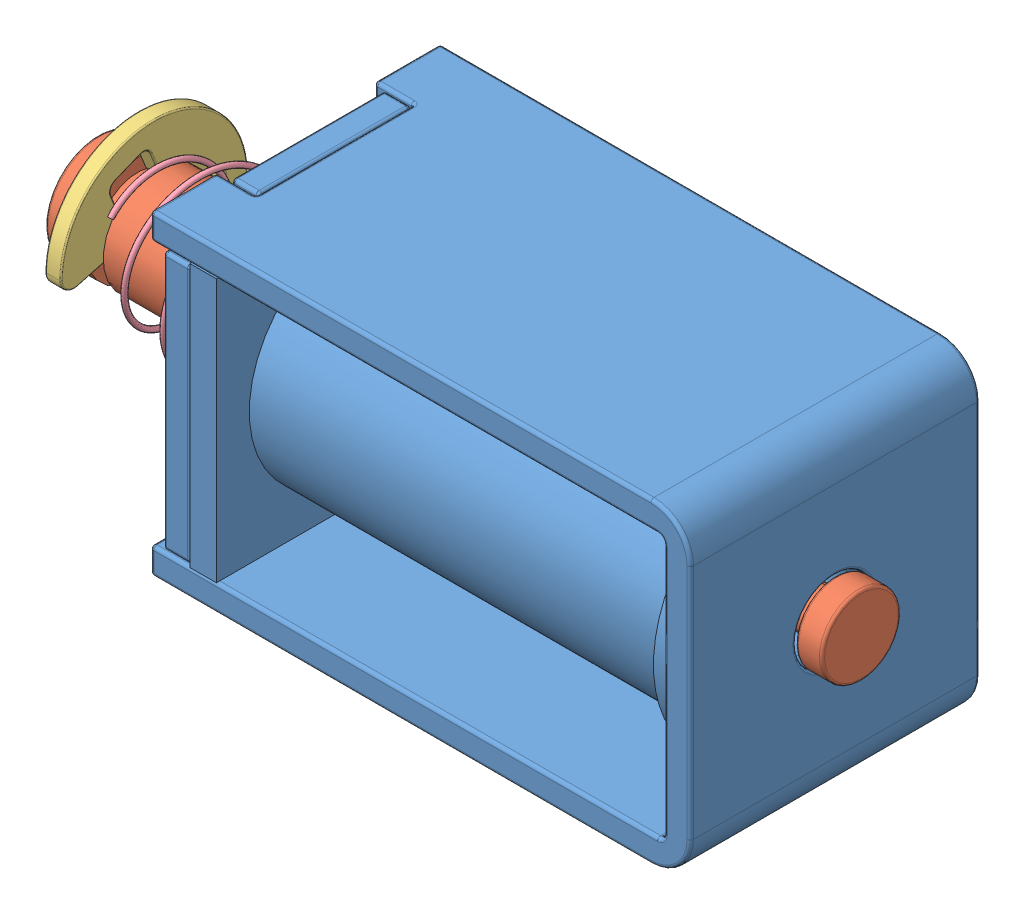
SolidWorks assembly Solenoid, configuration Default. Lengths in mm.
Overall size (29 12 11).
5 component instances, 4 part files, 3 mates.
Components (placement in the parent):
- Shell-1: Shell [Default] at origin size (20.5 12 11)
- Shaft Assem-1: Shaft Assem [Default] at (2.5 -6 5.5) x (0 0.575247 0.81798) z (1 0 0) size (7.1 6.76 29)
  - Shaft-1: Shaft [Default] at origin size (4 4 29)
  - Circlip-1: Circlip [Default] at (0 0 -8.45) size (7.1 5.79 0.6)
  - Spring-1: Spring [Default] at (0 0 -2.3) x (-1 0 0) z (0 0 -1) size (6.3 6.5 5.85)
Mates (geometry in assembly coordinates):
- Coincident1: coordinate: point of Shell-1; point of assembly
- Concentric1: concentric: cylinder of Shell-1 through (0 -6 5.5) axis (1 0 0) radius 1.5; cylinder of Shaft Assem-1/Shaft-1 through (20.5 -6 5.5) axis (-1 0 0) radius 0.775
- Coincident2: coincident: plane of Shell-1 through (20.5 0 11) normal (1 0 0); plane of Shaft Assem-1/Shaft-1 through (20.5 -6 5.5) normal (-1 0 0)
